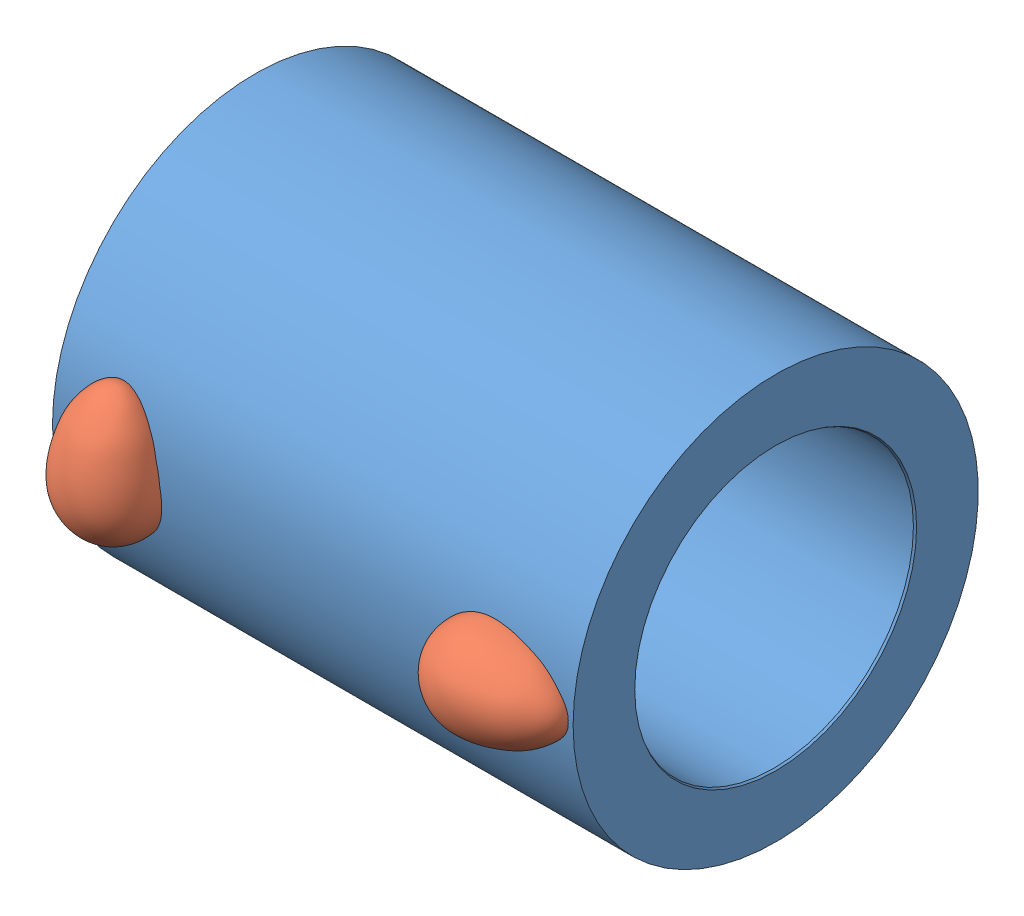
SolidWorks assembly grand oeuf CM-010835 09 Rouleaux bronze CuSn9P De 100-130, configuration Défaut. Lengths in mm.
Overall size (1629.84 1053.3 111.93).
3 component instances, 2 part files, 4 mates.
Components (placement in the parent):
- grand oeuf CM-010835 09 Rouleaux bronze CuSn9P-CuSn8 (UE9P)  De 100-130-1: grand oeuf CM-010835 09 Rouleaux bronze CuSn9P-CuSn8 (UE9P)  De 100-130 [Défaut] at (-74.901 0.2315 128.5) size (128.5 100 100)
- demi œuf de 32.5 mm de haut AVEC  le dessin carreau de ciment forme concave et convexe pour avoir une épaisseur de matière de 2 mm-1: demi œuf de 32.5 mm de haut AVEC  le dessin carreau de ciment forme concave et convexe pour avoir une épaisseur de matière de 2 mm [Défaut] at (-30.701 -18.7552 178.5) x (-1 0 0) z (0 0 -1) size (1032.5 549.5 24.66)
- demi œuf de 32.5 mm de haut AVEC  le dessin carreau de ciment forme concave et convexe pour avoir une épaisseur de matière de 2 mm-2: demi œuf de 32.5 mm de haut AVEC  le dessin carreau de ciment forme concave et convexe pour avoir une épaisseur de matière de 2 mm [Défaut] at (17.1354 -28.9685 178.5) x (0 1 0) z (0 0 -1) size (1032.5 549.5 24.66)
Mates (geometry in assembly coordinates):
- Coïncidente1: coincident anti-aligned: line of grand oeuf CM-010835 09 Rouleaux bronze CuSn9P-CuSn8 (UE9P)  De 100-130-1 through (-74.901 0.2315 178.5) axis (1 0 0); line of demi œuf de 32.5 mm de haut AVEC  le dessin carreau de ciment forme concave et convexe pour avoir une épaisseur de matière de 2 mm-1 through (-30.701 0.2315 178.5) axis (-1 0 0)
- Distance1: distance = 15 mm: line of demi œuf de 32.5 mm de haut AVEC  le dessin carreau de ciment forme concave et convexe pour avoir une épaisseur de matière de 2 mm-1 through (-59.901 16.4815 178.5) axis (0 -1 0); plane of grand oeuf CM-010835 09 Rouleaux bronze CuSn9P-CuSn8 (UE9P)  De 100-130-1 through (-74.901 34.7315 128.5) normal (-1 0 0)
- Coïncidente3: coincident: line of grand oeuf CM-010835 09 Rouleaux bronze CuSn9P-CuSn8 (UE9P)  De 100-130-1 through (-74.901 0.2315 178.5) axis (1 0 0); line of demi œuf de 32.5 mm de haut AVEC  le dessin carreau de ciment forme concave et convexe pour avoir une épaisseur de matière de 2 mm-2 through (52.3721 0.2315 178.5) axis (-1 0 0)
- Distance2: distance = 20 mm: line of demi œuf de 32.5 mm de haut AVEC  le dessin carreau de ciment forme concave et convexe pour avoir une épaisseur de matière de 2 mm-2 through (33.599 -28.9685 178.5) axis (0 1 0); plane of grand oeuf CM-010835 09 Rouleaux bronze CuSn9P-CuSn8 (UE9P)  De 100-130-1 through (53.599 34.7315 128.5) normal (1 0 0)
